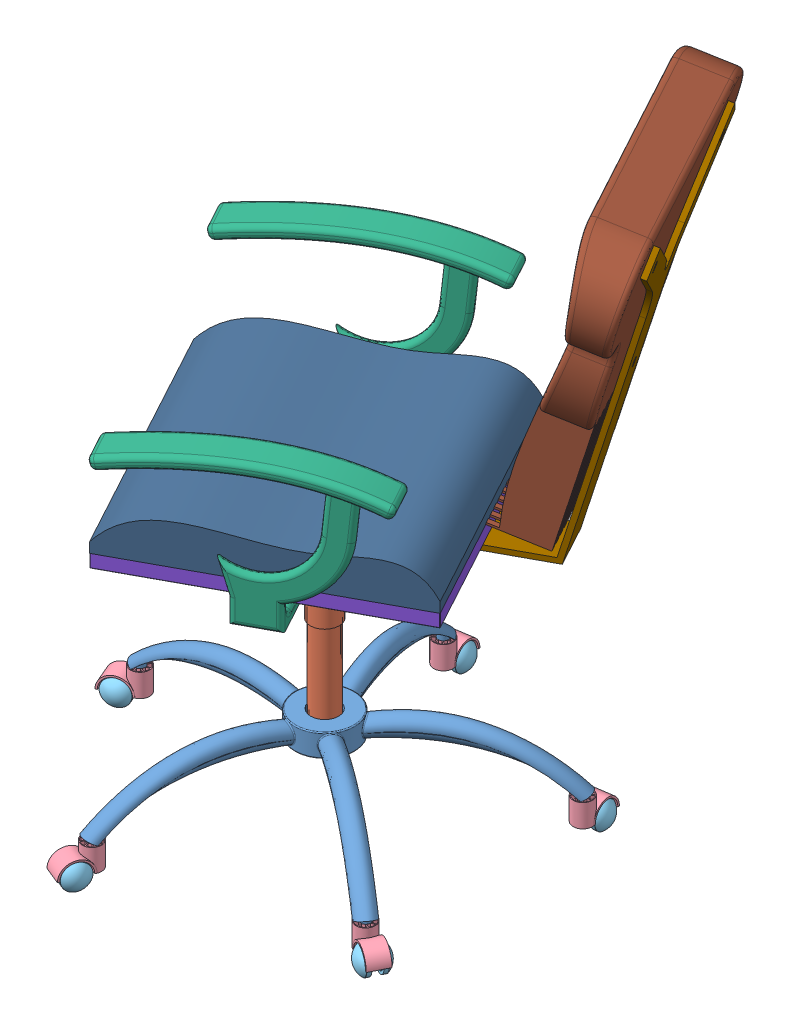
SolidWorks assembly modified executive chair, configuration Default. Lengths in mm.
Overall size (1055.52 1263.44 934.36).
36 component instances, 13 part files, 75 mates.
Components (placement in the parent):
- wheel arm-1: wheel arm [Default] at (135.514 345.0964 579.3777) size (699.95 120.74 735.89)
- shocker-1: shocker [Default] at (359.9655 322.5964 579.3777) size (57 400 57)
- shocker rest-1: shocker rest [Default] at (352.1531 722.5964 515.3339) x (-0.47671 0 -0.879061) z (0 1 0) size (80 80 46)
- caster wheel support-1: caster wheel support [Default] at (631.6111 215.0964 338.2758) x (0.989147 0 -0.146932) z (0.146932 0 0.989147) size (38 52.5 79)
- caster wheel support-2: caster wheel support [Default] at (224.0975 215.0964 205.9196) x (0.988901 0 -0.148573) z (0.148573 0 0.988901) size (38 52.5 79)
- caster wheel support-3: caster wheel support [Default] at (-24.6202 215.0964 608.6285) x (-0.392526 0 -0.919741) z (0.919741 0 -0.392526) size (38 52.5 79)
- caster wheel support-4: caster wheel support [Default] at (690.1444 215.0964 790.0351) x (-0.447618 0 0.894225) z (-0.894225 0 -0.447618) size (38 52.5 79)
- caster wheel support-5: caster wheel support [Default] at (253.4712 215.0964 960.9695) x (-0.924471 0 -0.381253) z (0.381253 0 -0.924471) size (38 52.5 79)
- caster wheel-1: caster wheel [Default] at (-35.63 214.8177 582.8839) x (0.486363 0.848744 -0.20757) z (-0.780624 0.528805 0.333154) size (49.78 20 49.78)
- caster wheel-2: caster wheel [Default] at (-28.5454 215.0964 599.4311) x (-0.396721 -0.90219 0.169312) z (-0.829781 0.431339 0.354133) size (49.78 20 49.78)
- caster wheel-3: caster wheel [Default] at (233.9865 215.0964 204.4339) x (0.113882 -0.642241 0.757996) z (-0.09542 -0.766503 -0.635113) size (49.78 20 49.78)
- caster wheel-4: caster wheel [Default] at (251.7867 215.0964 201.7596) x (0.111218 0.663052 0.740265) z (-0.098512 0.748573 -0.655693) size (49.78 20 49.78)
- caster wheel-5: caster wheel [Default] at (659.3072 215.0964 334.1617) x (-0.022078 0.988647 -0.148628) z (-0.145264 -0.150259 -0.977916) size (49.78 20 49.78)
- caster wheel-6: caster wheel [Default] at (641.5026 215.0964 336.8065) x (0.000681 -0.999989 0.004583) z (-0.146931 -0.004633 -0.989136) size (49.78 20 49.78)
- caster wheel-7: caster wheel [Default] at (685.6682 215.0964 798.9774) x (-0.594153 0.747347 -0.297413) z (-0.668296 -0.664434 -0.334526) size (49.78 20 49.78)
- caster wheel-8: caster wheel [Default] at (677.6111 215.0964 815.0734) x (0.739341 -0.562502 0.370089) z (-0.503003 -0.826796 -0.251786) size (49.78 20 49.78)
- caster wheel-9: caster wheel [Default] at (244.2265 215.0964 957.157) x (-0.335148 0.476691 0.812675) z (0.18174 0.879071 -0.440687) size (49.78 20 49.78)
- caster wheel-10: caster wheel [Default] at (227.586 215.0964 950.2944) x (-0.235491 -0.786433 0.571023) z (0.29983 -0.617676 -0.727034) size (49.78 20 49.78)
- mdified plate-1: mdified plate [Default] at (353.4146 729.5964 588.2749) x (0.47671 0 0.879061) z (0.879061 0 -0.47671) size (665.65 336.01 446.99)
- shocker liver-3: shocker liver [Default] at (339.3344 695.5964 562.3109) x (0.47671 0 0.879061) z (-0.686799 0.624172 0.372448) size (287.39 119.66 14.93)
- modified seat-1: modified seat [Default] at (480.1282 729.5964 580.4259) x (0.47671 0 0.879061) z (-0.879061 0 0.47671) size (510 25.31 510)
- modified back support-1: modified back support [Default] at (677.676 803.4159 361.2385) x (0.47671 0 0.879061) z (-0.847852 0.264089 0.459786) size (431.61 749.72 202.64)
- seat cushion-2: seat cushion [Default] at (451.8452 754.9104 733.3743) x (0.47671 0 0.879061) z (-0.879061 0 0.47671) size (510 122.16 510)
- modified back cushion-3: modified back cushion [Default] at (818.2107 1171.421 430.7636) x (0.47671 0 0.879061) z (-0.847852 0.264089 0.459786) size (601.39 620.35 100.05)
- screw jnt-1: screw jnt [Default] at (293.8258 729.5964 478.3923) x (-0.8629 0 -0.505375) z (-0.505375 0 0.8629) size (13.47 33 13.47)
- screw jnt-2: screw jnt [Default] at (413.0034 729.5964 698.1574) x (-0.052076 0 0.998643) z (0.998643 0 0.052076) size (13.47 33 13.47)
- screw jnt-3: screw jnt [Default] at (273.4161 750.5964 698.7748) x (0.4396 0 0.898194) z (0.898194 0 -0.4396) size (13.47 33 13.47)
- screw jnt-5: screw jnt [Default] at (489.665 750.5964 581.5041) x (-0.679617 0 0.733567) z (0.733567 0 0.679617) size (13.47 33 13.47)
- screw jnt-6: screw jnt [Default] at (217.1643 750.5964 595.0457) x (-0.850656 0 0.525723) z (0.525723 0 0.850656) size (13.47 33 13.47)
- screw jnt-7: screw jnt [Default] at (433.4132 750.5964 477.775) x (-0.569666 0 0.821876) z (0.821876 0 0.569666) size (13.47 33 13.47)
- rivet-1: rivet [Default] at (541.4807 719.5964 463.536) size (20 25 20)
- rivet-2: rivet [Default] at (515.8525 719.5964 500.1856) size (20 25 20)
- rivet-3: rivet [Default] at (560.5491 719.5964 498.6984) size (20 25 20)
- rivet-4: rivet [Default] at (755.416 1056.2054 370.2715) x (0.33944 -0.395832 0.853287) z (-0.407341 -0.879531 -0.245964) size (20 25 20)
- rivet-5: rivet [Default] at (903.7182 1345.5549 477.5483) x (0.431327 0.847852 0.308389) z (0.308389 -0.459786 0.832762) size (20 25 20)
- rivet-6: rivet [Default] at (746.4039 1345.5549 187.4583) x (0.431327 0.847852 0.308389) z (0.308389 -0.459786 0.832762) size (20 25 20)
Mates (geometry in assembly coordinates):
- Concentric1: concentric anti-aligned: cylinder of wheel arm-1 through (359.9655 244.8146 579.3777) axis (0 1 0) radius 27.5; cylinder of shocker-1 through (359.9655 522.5964 579.3777) axis (0 -1 0) radius 25
- Coincident1: coincident aligned: plane of wheel arm-1 through (359.9655 322.5964 579.3777) normal (0 -1 0); plane of shocker-1 through (359.9655 322.5964 579.3777) normal (0 -1 0)
- Coincident2: coincident anti-aligned: plane of shocker-1 through (359.9655 722.5964 579.3777) normal (0 1 0); plane of shocker rest-1 through (343.2509 722.5964 632.4642) normal (0 -1 0)
- Concentric2: concentric anti-aligned: cylinder of shocker-1 through (359.9655 722.5964 579.3777) axis (0 -1 0) radius 28.5; cylinder of shocker rest-1 through (359.9655 679.5964 579.3777) axis (0 1 0) radius 30
- Coincident5: coincident anti-aligned: plane of wheel arm-1 through (654.8129 260.0964 365.1585) normal (0 -1 0); plane of caster wheel support-1 through (654.8129 260.0964 365.1585) normal (0 1 0)
- Coincident6: coincident aligned: cylinder of wheel arm-1 through (654.8129 260.0964 365.1585) axis (0 1 0) radius 5; circle of caster wheel support-1
- Coincident7: coincident anti-aligned: plane of wheel arm-1 through (247.3438 260.0964 232.7638) normal (0 -1 0); plane of caster wheel support-2 through (247.3438 260.0964 232.7638) normal (0 1 0)
- Coincident8: coincident aligned: cylinder of wheel arm-1 through (247.3438 260.0964 232.7638) axis (0 1 0) radius 5; circle of caster wheel support-2
- Coincident9: coincident anti-aligned: plane of wheel arm-1 through (-4.486 260.0964 579.3777) normal (0 -1 0); plane of caster wheel support-3 through (-4.486 260.0964 579.3777) normal (0 1 0)
- Coincident10: coincident aligned: cylinder of wheel arm-1 through (-4.486 260.0964 579.3777) axis (0 1 0) radius 5; circle of caster wheel support-3
- Coincident11: coincident anti-aligned: plane of wheel arm-1 through (654.8129 260.0964 793.5969) normal (0 -1 0); plane of caster wheel support-4 through (654.8129 260.0964 793.5969) normal (0 1 0)
- Coincident12: coincident aligned: cylinder of wheel arm-1 through (654.8129 260.0964 793.5969) axis (0 1 0) radius 5; circle of caster wheel support-4
- Coincident14: coincident anti-aligned: plane of wheel arm-1 through (247.3438 260.0964 925.9916) normal (0 -1 0); plane of caster wheel support-5 through (247.3438 260.0964 925.9916) normal (0 1 0)
- Coincident15: coincident aligned: cylinder of wheel arm-1 through (247.3438 260.0964 925.9916) axis (0 1 0) radius 5; circle of caster wheel support-5
- Coincident34: coincident anti-aligned: plane of caster wheel support-3 through (-35.6109 215.0964 582.8758) normal (-0.392526 0 -0.919741); circle of caster wheel-1
- Concentric27: concentric anti-aligned: cylinder of caster wheel support-3 through (-39.5362 215.0964 573.6784) axis (0.392526 0 0.919741) radius 5.5; circle of caster wheel-2
- Coincident39: coincident anti-aligned: plane of caster wheel support-3 through (-28.5454 215.0964 599.4311) normal (0.392526 0 0.919741); plane of caster wheel-2 through (-28.5454 215.0964 599.4311) normal (-0.392526 0 -0.919741)
- Concentric28: concentric anti-aligned: circle of caster wheel support-2; circle of caster wheel-3
- Coincident40: coincident anti-aligned: plane of caster wheel support-2 through (233.9865 215.0964 204.4339) normal (-0.988901 0 0.148573); plane of caster wheel-3 through (233.9865 215.0964 204.4339) normal (0.988901 0 -0.148573)
- Concentric29: concentric anti-aligned: circle of caster wheel support-2; circle of caster wheel-4
- Coincident42: coincident anti-aligned: plane of caster wheel support-2 through (251.7867 215.0964 201.7596) normal (0.988901 0 -0.148573); plane of caster wheel-4 through (251.7867 215.0964 201.7596) normal (-0.988901 0 0.148573)
- Concentric30: concentric anti-aligned: circle of caster wheel support-1; circle of caster wheel-5
- Coincident43: coincident anti-aligned: plane of caster wheel support-1 through (659.3072 215.0964 334.1617) normal (0.989147 0 -0.146932); plane of caster wheel-5 through (659.3072 215.0964 334.1617) normal (-0.989147 0 0.146932)
- Concentric31: concentric anti-aligned: circle of caster wheel support-1; circle of caster wheel-6
- Coincident44: coincident anti-aligned: plane of caster wheel support-1 through (641.5026 215.0964 336.8065) normal (-0.989147 0 0.146932); plane of caster wheel-6 through (641.5026 215.0964 336.8065) normal (0.989147 0 -0.146932)
- Concentric32: concentric anti-aligned: circle of caster wheel support-4; circle of caster wheel-7
- Coincident45: coincident anti-aligned: plane of caster wheel support-4 through (685.6682 215.0964 798.9774) normal (0.447618 0 -0.894225); plane of caster wheel-7 through (685.6682 215.0964 798.9774) normal (-0.447618 0 0.894225)
- Concentric33: concentric anti-aligned: circle of caster wheel support-4; circle of caster wheel-8
- Coincident46: coincident: moEndPointRef_w of caster wheel support-4; plane of caster wheel-8 through (677.6111 215.0964 815.0734) normal (0.447618 0 -0.894225)
- Concentric34: concentric anti-aligned: circle of caster wheel support-5; circle of caster wheel-10
- Coincident47: coincident anti-aligned: plane of caster wheel support-5 through (227.586 215.0964 950.2944) normal (-0.924471 0 -0.381253); plane of caster wheel-10 through (227.586 215.0964 950.2944) normal (0.924471 0 0.381253)
- Concentric35: concentric anti-aligned: circle of caster wheel support-5; circle of caster wheel-9
- Coincident48: coincident anti-aligned: plane of caster wheel support-5 through (244.2265 215.0964 957.157) normal (0.924471 0 0.381253); plane of caster wheel-9 through (244.2265 215.0964 957.157) normal (-0.924471 0 -0.381253)
- Coincident49: coincident anti-aligned: plane of shocker rest-1 through (343.2509 725.5964 632.4642) normal (0 1 0); plane of mdified plate-1 through (485.2586 725.5964 768.4657) normal (0 -1 0)
- Concentric36: concentric anti-aligned: cylinder of shocker rest-1 through (369.6228 695.5964 618.1629) axis (-0.47671 0 -0.879061) radius 6; cylinder of mdified plate-1 through (321.4891 695.5964 529.4037) axis (0.47671 0 0.879061) radius 6
- Coincident51: coincident anti-aligned: plane of shocker rest-1 through (305.1141 682.5964 562.1394) normal (-0.47671 0 -0.879061); plane of mdified plate-1 through (305.1141 682.5964 562.1394) normal (0.47671 0 0.879061)
- Concentric37: concentric anti-aligned: cylinder of mdified plate-1 through (321.4891 695.5964 529.4037) axis (0.47671 0 0.879061) radius 6; cylinder of shocker liver-3 through (377.2501 695.5964 632.2279) axis (-0.47671 0 -0.879061) radius 6
- Coincident52: coincident anti-aligned: plane of mdified plate-1 through (403.6219 725.5964 617.9266) normal (0.47671 0 0.879061); plane of shocker liver-3 through (377.2501 695.5964 632.2279) normal (-0.47671 0 -0.879061)
- Coincident53: coincident anti-aligned: plane of mdified plate-1 through (485.2586 729.5964 768.4657) normal (0 1 0); plane of modified seat-1 through (480.1282 729.5964 580.4259) normal (0 -1 0)
- Concentric38: concentric aligned: cylinder of mdified plate-1 through (273.4161 768.5964 698.7748) axis (0 -1 0) radius 6; cylinder of modified seat-1 through (273.4161 744.5964 698.7748) axis (0 -1 0) radius 6
- Concentric39: concentric aligned: cylinder of mdified plate-1 through (217.1643 768.5964 595.0457) axis (0 -1 0) radius 6; cylinder of modified seat-1 through (217.1643 744.5964 595.0457) axis (0 -1 0) radius 6
- Coincident54: coincident anti-aligned: plane of modified seat-1 through (480.1282 729.5964 580.4259) normal (0 -1 0); plane of modified back support-1 through (693.6977 729.5964 454.932) normal (0 1 0)
- Concentric40: concentric anti-aligned: cylinder of modified seat-1 through (560.5491 744.5964 498.6984) axis (0 -1 0) radius 6; cylinder of modified back support-1 through (560.5491 714.5964 498.6984) axis (0 1 0) radius 6
- Concentric41: concentric anti-aligned: cylinder of modified seat-1 through (541.4807 744.5964 463.536) axis (0 -1 0) radius 6; cylinder of modified back support-1 through (541.4807 714.5964 463.536) axis (0 1 0) radius 6
- Coincident55: coincident aligned: plane of modified seat-1 through (456.0139 829.5964 242.5533) normal (-0.47671 0 -0.879061); plane of seat cushion-2 through (456.0139 774.9104 242.5533) normal (-0.47671 0 -0.879061)
- Coincident56: coincident anti-aligned: plane of modified seat-1 through (-0.6673 754.9104 468.1612) normal (0 1 0); plane of seat cushion-2 through (451.8452 754.9104 733.3743) normal (0 -1 0)
- Coincident57: coincident aligned: plane of modified seat-1 through (7.6931 829.5964 485.6756) normal (-0.879061 0 0.47671); plane of seat cushion-2 through (7.6931 774.9104 485.6756) normal (-0.879061 0 0.47671)
- Concentric48: concentric anti-aligned: cylinder of modified back support-1 through (759.1217 1341.5936 180.5615) axis (-0.847852 0.264089 0.459786) radius 6; cylinder of modified back cushion-3 through (725.2076 1352.1571 198.953) axis (0.847852 -0.264089 -0.459786) radius 6
- Concentric49: concentric anti-aligned: cylinder of modified back support-1 through (916.436 1341.5936 470.6515) axis (-0.847852 0.264089 0.459786) radius 6; cylinder of modified back cushion-3 through (882.5219 1352.1571 489.043) axis (0.847852 -0.264089 -0.459786) radius 6
- Concentric50: concentric anti-aligned: cylinder of modified back support-1 through (768.1338 1052.244 363.3747) axis (-0.847852 0.264089 0.459786) radius 6; cylinder of modified back cushion-3 through (734.2197 1062.8076 381.7661) axis (0.847852 -0.264089 -0.459786) radius 6
- Coincident60: coincident anti-aligned: plane of modified back support-1 through (773.1789 1059.8117 411.8298) normal (-0.847852 0.264089 0.459786); plane of modified back cushion-3 through (672.2578 1175.1249 159.4969) normal (0.847852 -0.264089 -0.459786)
- Concentric51: concentric aligned: cylinder of mdified plate-1 through (293.8258 604.5964 478.3923) axis (0 1 0) radius 6; cylinder of screw jnt-1 through (293.8258 704.5964 478.3923) axis (0 1 0) radius 6
- Coincident61: coincident anti-aligned: plane of mdified plate-1 through (293.235 704.5964 393.3944) normal (0 -1 0); plane of screw jnt-1 through (293.8258 704.5964 478.3923) normal (0 1 0)
- Concentric52: concentric aligned: cylinder of mdified plate-1 through (413.0034 604.5964 698.1574) axis (0 1 0) radius 6; cylinder of screw jnt-2 through (413.0034 704.5964 698.1574) axis (0 1 0) radius 6
- Coincident62: coincident anti-aligned: plane of mdified plate-1 through (483.9191 704.5964 745.0186) normal (0 -1 0); plane of screw jnt-2 through (413.0034 704.5964 698.1574) normal (0 1 0)
- Concentric54: concentric anti-aligned: cylinder of mdified plate-1 through (273.4161 768.5964 698.7748) axis (0 -1 0) radius 6; cylinder of screw jnt-3 through (273.4161 725.5964 698.7748) axis (0 1 0) radius 6
- Coincident63: coincident anti-aligned: plane of mdified plate-1 through (485.2586 725.5964 768.4657) normal (0 -1 0); plane of screw jnt-3 through (273.4161 725.5964 698.7748) normal (0 1 0)
- Concentric55: concentric anti-aligned: cylinder of mdified plate-1 through (489.665 768.5964 581.5041) axis (0 -1 0) radius 6; cylinder of screw jnt-5 through (489.665 725.5964 581.5041) axis (0 1 0) radius 6
- Coincident64: coincident anti-aligned: plane of mdified plate-1 through (485.2586 725.5964 768.4657) normal (0 -1 0); plane of screw jnt-5 through (489.665 725.5964 581.5041) normal (0 1 0)
- Concentric56: concentric anti-aligned: cylinder of mdified plate-1 through (217.1643 768.5964 595.0457) axis (0 -1 0) radius 6; cylinder of screw jnt-6 through (217.1643 725.5964 595.0457) axis (0 1 0) radius 6
- Coincident65: coincident aligned: plane of mdified plate-1 through (485.2586 725.5964 768.4657) normal (0 -1 0); circle of screw jnt-6
- Concentric57: concentric anti-aligned: cylinder of modified seat-1 through (433.4132 744.5964 477.775) axis (0 -1 0) radius 6; cylinder of screw jnt-7 through (433.4132 725.5964 477.775) axis (0 1 0) radius 6
- Coincident66: coincident anti-aligned: plane of mdified plate-1 through (485.2586 725.5964 768.4657) normal (0 -1 0); plane of screw jnt-7 through (433.4132 725.5964 477.775) normal (0 1 0)
- Concentric58: concentric anti-aligned: cylinder of modified back support-1 through (541.4807 714.5964 463.536) axis (0 1 0) radius 6; cylinder of rivet-1 through (541.4807 739.5964 463.536) axis (0 -1 0) radius 6
- Coincident67: coincident anti-aligned: plane of modified back support-1 through (700.4049 719.5964 451.2947) normal (0 -1 0); plane of rivet-1 through (541.4807 719.5964 463.536) normal (0 1 0)
- Concentric59: concentric anti-aligned: cylinder of modified back support-1 through (560.5491 714.5964 498.6984) axis (0 1 0) radius 6; cylinder of rivet-3 through (560.5491 739.5964 498.6984) axis (0 -1 0) radius 6
- Coincident68: coincident anti-aligned: plane of modified back support-1 through (700.4049 719.5964 451.2947) normal (0 -1 0); plane of rivet-3 through (560.5491 719.5964 498.6984) normal (0 1 0)
- Concentric60: concentric anti-aligned: cylinder of modified back support-1 through (515.8525 714.5964 500.1856) axis (0 1 0) radius 6; cylinder of rivet-2 through (515.8525 739.5964 500.1856) axis (0 -1 0) radius 6
- Coincident69: coincident anti-aligned: plane of modified back support-1 through (700.4049 719.5964 451.2947) normal (0 -1 0); plane of rivet-2 through (515.8525 719.5964 500.1856) normal (0 1 0)
- Concentric61: concentric anti-aligned: cylinder of modified back support-1 through (768.1338 1052.244 363.3747) axis (-0.847852 0.264089 0.459786) radius 6; cylinder of rivet-4 through (738.459 1061.4872 379.4672) axis (0.847852 -0.264089 -0.459786) radius 6
- Coincident70: coincident aligned: plane of modified back support-1 through (781.6575 1057.1708 407.2319) normal (0.847852 -0.264089 -0.459786); plane of rivet-4 through (759.6553 1054.8849 367.9725) normal (0.847852 -0.264089 -0.459786)
- Concentric62: concentric anti-aligned: cylinder of modified back support-1 through (916.436 1341.5936 470.6515) axis (-0.847852 0.264089 0.459786) radius 6; cylinder of rivet-5 through (886.7612 1350.8367 486.744) axis (0.847852 -0.264089 -0.459786) radius 6
- Coincident71: coincident aligned: plane of modified back support-1 through (781.6575 1057.1708 407.2319) normal (0.847852 -0.264089 -0.459786); plane of rivet-5 through (907.9575 1344.2344 475.2494) normal (0.847852 -0.264089 -0.459786)
- Coincident72: coincident: plane of modified back support-1 through (781.6575 1057.1708 407.2319) normal (0.847852 -0.264089 -0.459786); plane of rivet-6 through (750.6431 1344.2344 185.1594) normal (0.847852 -0.264089 -0.459786)
- Concentric64: concentric anti-aligned: cylinder of modified back support-1 through (759.1217 1341.5936 180.5615) axis (-0.847852 0.264089 0.459786) radius 6; cylinder of rivet-6 through (729.4468 1350.8367 196.6541) axis (0.847852 -0.264089 -0.459786) radius 6
